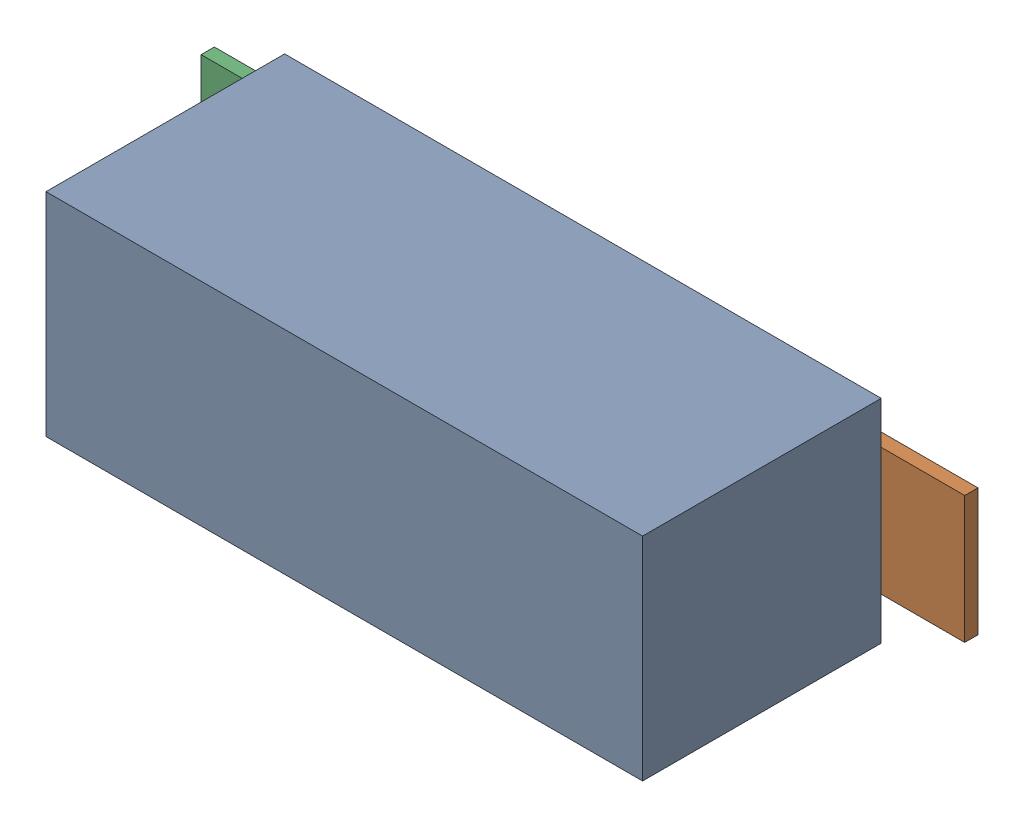
SolidWorks assembly TROYKA_AMPLIFIER_D__BLM41PG102SZ1B v1, configuration По умолчанию. Lengths in mm.
Overall size (5.76 1.6 1.9).
2 component instances, 2 part files, 0 mates.
Components (placement in the parent):
- TROYKA_AMPLIFIER_D_Body-1: TROYKA_AMPLIFIER_D_Body [По умолчанию] at (0 0 0.1) size (4.5 1.6 1.8)
- TROYKA_AMPLIFIER_D_Pins-1: TROYKA_AMPLIFIER_D_Pins [По умолчанию] at origin size (5.76 0.96 0.1)
